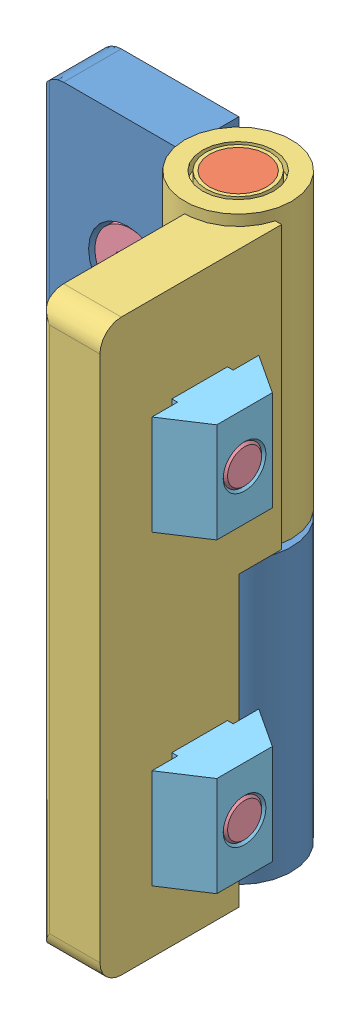
SolidWorks assembly HHPNLK-B6-SET, configuration Default. Lengths in mm.
Overall size (43.9 81.5 43.9).
11 component instances, 5 part files, 25 mates.
Components (placement in the parent):
- hinge_1-1: hinge_1 [Default] at (-5.4713 22.3868 78.8004) size (35 80 15.6)
- perno-1: perno [Default] at (-5.4713 22.3868 78.8004) size (8 81.5 8)
- hinge_2-1: hinge_2 [Default] at (-5.4713 22.3868 78.8004) x (0 0 1) z (-1 0 0) size (35 81.5 15.6)
- screw-1: screw [Default] at (-5.4713 22.3868 78.8004) size (10 10 16)
- nut-1: nut [Default] at (-36.4713 22.3868 78.0004) size (15 14 6.3)
- screw-2: screw [Default] at (-5.4713 22.3868 109.8004) x (0 0 1) z (-1 0 0) size (10 10 16)
- screw-3: screw [Default] at (-5.4713 -20.6132 78.8004) size (10 10 16)
- screw-4: screw [Default] at (-5.4713 -20.6132 109.8004) x (0 0 1) z (-1 0 0) size (10 10 16)
- nut-2: nut [Default] at (-36.4713 -20.6132 78.0004) size (15 14 6.3)
- nut-3: nut [Default] at (-4.6713 22.3868 78.8004) x (0 0 1) z (-1 0 0) size (15 14 6.3)
- nut-4: nut [Default] at (-4.6713 -20.6132 78.8004) x (0 0 1) z (-1 0 0) size (15 14 6.3)
Mates (geometry in assembly coordinates):
- Concentric1: concentric aligned: cylinder of hinge_1-1 through (-5.4713 -17.6132 78.8004) axis (0 -1 0) radius 4; cylinder of perno-1 through (-5.4713 63.8868 78.8004) axis (0 -1 0) radius 4
- Coincident1: coincident aligned: plane of hinge_1-1 through (-5.4713 -17.6132 78.8004) normal (0 -1 0); plane of perno-1 through (-5.4713 -17.6132 78.8004) normal (0 -1 0)
- Concentric2: concentric anti-aligned: cylinder of perno-1 through (-5.4713 63.8868 78.8004) axis (0 -1 0) radius 4; cylinder of hinge_2-1 through (-5.4713 63.8868 78.8004) axis (0 1 0) radius 4
- Coincident2: coincident aligned: plane of hinge_1-1 through (-5.4713 62.3868 78.8004) normal (0 1 0); plane of hinge_2-1 through (-5.4713 62.3868 78.8004) normal (0 1 0)
- Concentric3: concentric aligned: cylinder of hinge_1-1 through (-20.9713 43.8868 78.8004) axis (0 0 1) radius 3.25; cylinder of screw-1 through (-20.9713 43.8868 62.4004) axis (0 0 1) radius 3
- Concentric4: concentric aligned: circle of hinge_2-1; cylinder of screw-2 through (11.0507 43.8868 94.1703) axis (-0.999969 0 0.007903) radius 3
- Concentric5: concentric aligned: cylinder of hinge_1-1 through (-20.9713 0.8868 78.8004) axis (0 0 1) radius 3.25; cylinder of screw-3 through (-20.9713 0.8868 62.4004) axis (0 0 1) radius 3
- Concentric6: concentric aligned: cylinder of hinge_2-1 through (-5.3488 0.8868 94.2999) axis (-0.999969 0 0.007903) radius 3.25; cylinder of screw-4 through (11.0507 0.8868 94.1703) axis (-0.999969 0 0.007903) radius 3
- Coincident3: coincident anti-aligned: plane of hinge_1-1 through (-17.7213 43.8868 74.4004) normal (0 0 1); circle of screw-1
- Coincident4: coincident anti-aligned: plane of hinge_2-1 through (-0.9233 43.8868 97.515) normal (-0.999969 0 0.007903); circle of screw-2
- Coincident5: coincident anti-aligned: plane of hinge_2-1 through (-0.9233 0.8868 97.515) normal (-0.999969 0 0.007903); circle of screw-4
- Coincident6: coincident anti-aligned: plane of hinge_1-1 through (-17.7213 0.8868 74.4004) normal (0 0 1); circle of screw-3
- Coincident7: coincident aligned: plane of screw-1 through (-20.9713 43.8868 62.4004) normal (0 0 -1); plane of nut-1 through (-17.0713 36.8868 62.4004) normal (0 0 -1)
- Concentric7: concentric aligned: cylinder of screw-1 through (-20.9713 43.8868 62.4004) axis (0 0 1) radius 3; cylinder of nut-1 through (-20.9713 43.8868 68.7004) axis (0 0 1) radius 2.4585
- Concentric8: concentric aligned: cylinder of screw-3 through (-20.9713 0.8868 62.4004) axis (0 0 1) radius 3; cylinder of nut-2 through (-20.9713 0.8868 68.7004) axis (0 0 1) radius 2.4585
- Concentric9: concentric aligned: cylinder of screw-2 through (11.0507 43.8868 94.1703) axis (-0.999969 0 0.007903) radius 3; cylinder of nut-3 through (4.7509 43.8868 94.2201) axis (-0.999969 0 0.007903) radius 2.4585
- Concentric10: concentric anti-aligned: cylinder of screw-4 through (11.0507 0.8868 94.1703) axis (-0.999969 0 0.007903) radius 3; circle of nut-4
- Coincident8: coincident aligned: plane of screw-3 through (-20.9713 0.8868 62.4004) normal (0 0 -1); plane of nut-2 through (-17.0713 -6.1132 62.4004) normal (0 0 -1)
- Coincident9: coincident aligned: plane of screw-4 through (11.0507 0.8868 94.1703) normal (0.999969 0 -0.007903); plane of nut-4 through (11.0815 -6.1132 98.0701) normal (0.999969 0 -0.007903)
- Coincident10: coincident aligned: plane of screw-2 through (11.0507 43.8868 94.1703) normal (0.999969 0 -0.007903); plane of nut-3 through (11.0815 36.8868 98.0701) normal (0.999969 0 -0.007903)
- Parallel1: parallel aligned: plane of hinge_2-1 through (-5.4713 62.3868 78.8004) normal (0 1 0); plane of nut-3 through (-4.6713 50.8868 78.794) normal (0 1 0)
- Parallel2: parallel aligned: plane of nut-1 through (-36.4713 50.8868 78.0004) normal (0 1 0); plane of nut-3 through (-4.6713 50.8868 78.794) normal (0 1 0)
- Parallel3: parallel aligned: plane of nut-3 through (-4.6713 50.8868 78.794) normal (0 1 0); plane of nut-4 through (-4.6713 7.8868 78.794) normal (0 1 0)
- Coincident15: coincident aligned: plane of nut-2 through (-36.4713 7.8868 78.0004) normal (0 1 0); plane of nut-4 through (-4.6713 7.8868 78.794) normal (0 1 0)
- Angle1: planar angle = 1.570796 rad anti-aligned: line of hinge_1-1 through (-13.4713 62.3868 70.7004) axis (-1 0 0); line of hinge_2-1 through (2.6287 62.3868 103.3004) axis (0 0 -1)
